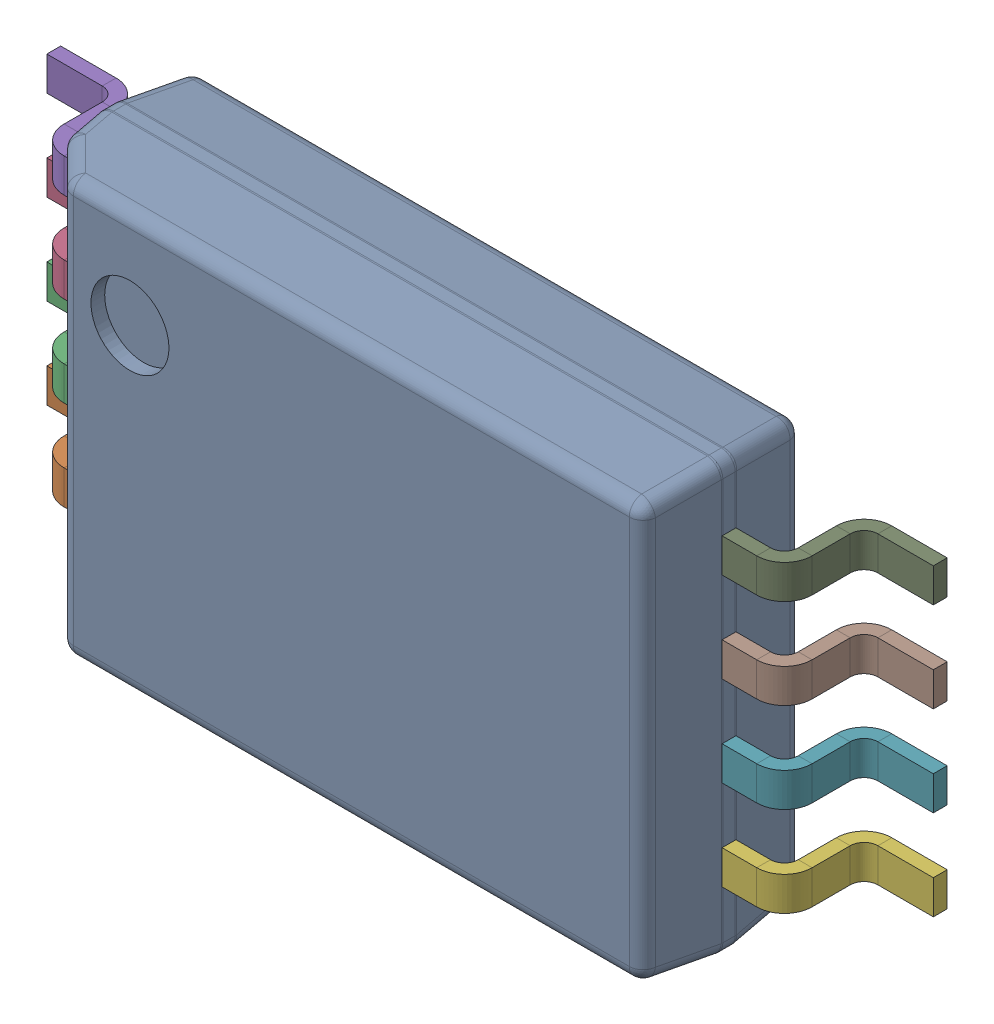
SolidWorks assembly U19.step, configuration Default. Lengths in mm.
Overall size (6.4 4.19 1.2).
12 component instances, 3 part files, 0 mates.
Components (placement in the parent):
- 6297729728.step-1: 6297729728.step [Default] at (24.9428 -5.969 0) x (1 0 0) z (0 0 1) size (6.4 4.19 1.2)
  - Body (11).step-1: Body (11).step [Default] at (-2.25 -1.55 0) size (4.5 3.1 1.15)
    - Open CASCADE STEP translator 6.8 2.2.1 (3).step-1: Open CASCADE STEP translator 6.8 2.2.1 (3).step [Default] at origin size (4.5 3.1 1.15)
  - Open CASCADE STEP translator 6.8 2.1 (3).step-1: Open CASCADE STEP translator 6.8 2.1 (3).step [Default] at (-2.25 -1.55 0.001) size (0.57 0.57 0.01)
  - Leader.step-1: Leader.step [Default] at (-2.25 -0.975 0) x (-1 0 0) z (0 0 1) size (0.95 0.24 0.68)
  - Leader.step-2: Leader.step [Default] at (-2.25 -0.325 0) x (-1 0 0) z (0 0 1) size (0.95 0.24 0.68)
  - Leader.step-3: Leader.step [Default] at (-2.25 0.325 0) x (-1 0 0) z (0 0 1) size (0.95 0.24 0.68)
  - Leader.step-4: Leader.step [Default] at (-2.25 0.975 0) x (-1 0 0) z (0 0 1) size (0.95 0.24 0.68)
  - Leader.step-5: Leader.step [Default] at (2.25 -0.975 0) size (0.95 0.24 0.68)
  - Leader.step-6: Leader.step [Default] at (2.25 -0.325 0) size (0.95 0.24 0.68)
  - Leader.step-7: Leader.step [Default] at (2.25 0.325 0) size (0.95 0.24 0.68)
  - Leader.step-8: Leader.step [Default] at (2.25 0.975 0) size (0.95 0.24 0.68)
